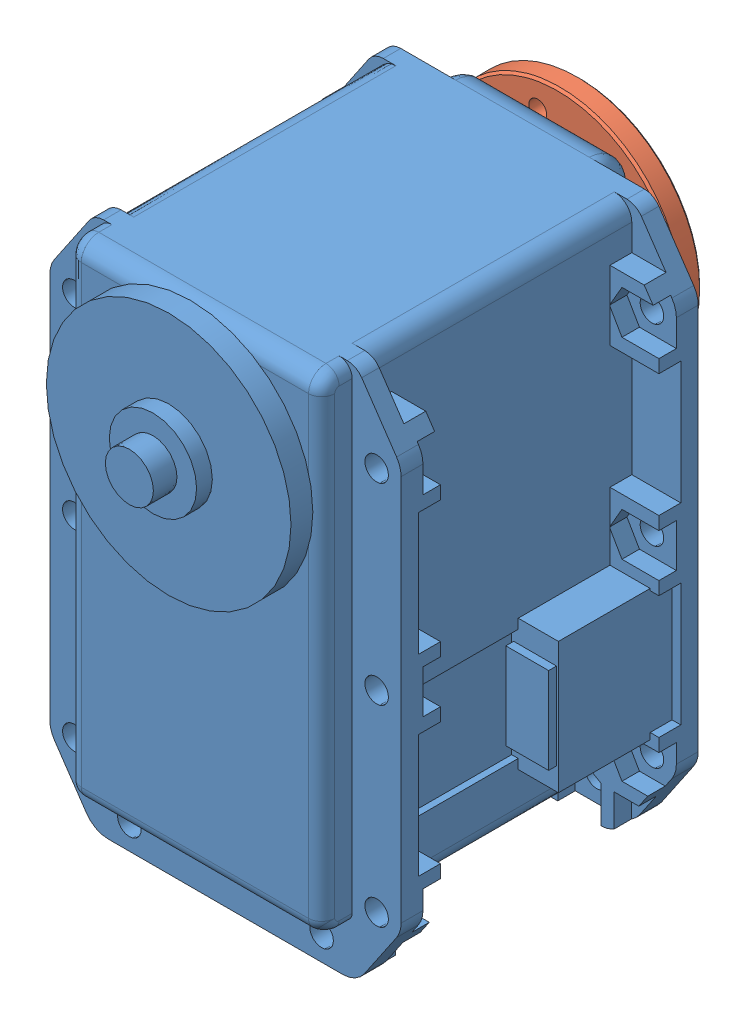
SolidWorks assembly 64_bearing, configuration Default. Lengths in mm.
Overall size (40.2 64.7 53.58).
5 component instances, 5 part files, 8 mates.
Components (placement in the parent):
- MX-64T_step-1: MX-64T_step [Default] at (11.6566 50.7443 49.8736) size (40.2 62.1 50)
- HN05-I101_2017-1: HN05-I101_2017 [Default] at (11.6566 50.7443 26.3536) x (-0.978167 -0.207821 0) z (0.207821 -0.978167 0) size (28 3.8 28)
- MF128ZZ_2017-1: MF128ZZ_2017 [Default] at (11.6566 50.7443 30.0736) x (-0.981893 -0.189437 0) z (0.189437 -0.981893 0) size (14 3.48 14)
- RX64-CAP_2017-1: RX64-CAP_2017 [Default] at (11.6566 50.7443 26.5936) x (-0.772804 -0.634645 0) z (0 0 -1) size (9.5 9.5 2.2)
- WB_M2.5X8_2017-1: WB_M2.5X8_2017 [Default] at (11.6566 50.7443 24.2936) x (0 0 1) z (-0.923728 -0.383049 0) size (4.5 4.5 4.5)
Mates (geometry in assembly coordinates):
- Concentric1: concentric aligned: cylinder of MX-64T_step-1 through (11.6566 50.7443 50.9736) axis (0 0 -1) radius 4; cylinder of HN05-I101_2017-1 through (11.6566 50.7443 26.3536) axis (0 0 -1) radius 6
- Coincident1: coincident aligned: cylinder of HN05-I101_2017-1 through (11.6566 50.7443 26.3536) axis (0 0 -1) radius 6; circle of MF128ZZ_2017-1
- Coincident2: coincident anti-aligned: plane of HN05-I101_2017-1 through (5.7876 49.4974 27.3536) normal (0 0 -1); plane of MF128ZZ_2017-1 through (4.7834 49.4183 27.3536) normal (0 0 1)
- Concentric2: concentric aligned: cylinder of MF128ZZ_2017-1 through (11.6566 50.7443 30.0736) axis (0 0 -1) radius 4; cylinder of RX64-CAP_2017-1 through (11.6566 50.7443 27.7936) axis (0 0 -1) radius 4
- Coincident3: coincident anti-aligned: plane of MF128ZZ_2017-1 through (7.7291 49.9866 26.5936) normal (0 0 -1); plane of RX64-CAP_2017-1 through (8.1017 47.825 26.5936) normal (0 0 1)
- Concentric3: concentric aligned: cylinder of RX64-CAP_2017-1 through (11.6566 50.7443 27.7936) axis (0 0 -1) radius 1.55; cylinder of WB_M2.5X8_2017-1 through (11.6566 50.7443 34.7936) axis (0 0 -1) radius 1.25
- Coincident4: coincident anti-aligned: plane of RX64-CAP_2017-1 through (10.3429 49.6654 26.7936) normal (0 0 -1); plane of WB_M2.5X8_2017-1 through (10.7948 52.8227 26.7936) normal (0 0 1)
- Coincident5: coincident anti-aligned: plane of MX-64T_step-1 through (11.6566 50.7443 30.0736) normal (0 0 -1); plane of MF128ZZ_2017-1 through (5.7653 49.6077 30.0736) normal (0 0 1)
